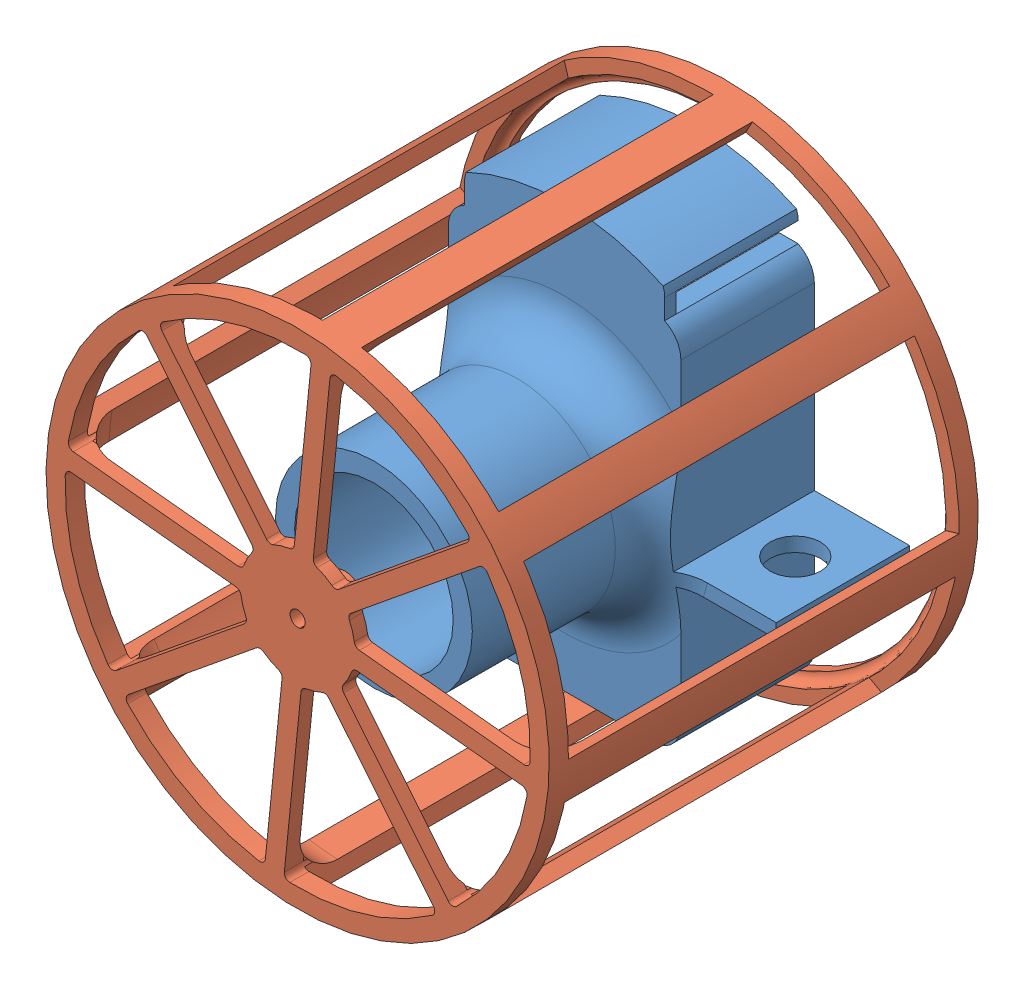
SolidWorks assembly Dumb Bot, configuration Default. Lengths in mm.
Overall size (90.82 90.82 57.15).
2 component instances, 2 part files, 2 mates.
Components (placement in the parent):
- Fly Wheel-1: Fly Wheel [Default] at (-42.9691 26.6526 21.4471) size (43.69 56.32 43.18)
- Case-1: Case [Default] at (-42.9691 26.6526 31.6071) x (0.473817 0.880623 0) z (0 0 1) size (67.06 67.06 57.15)
Mates (geometry in assembly coordinates):
- Concentric1: concentric aligned: cylinder of Fly Wheel-1 through (-42.9691 26.6526 21.4471) axis (0 0 1) radius 10.5705; cylinder of Case-1 through (-42.9691 26.6526 31.6071) axis (0 0 1) radius 1.016
- Distance1: distance = 3.81 mm anti-aligned: plane of Case-1 through (-43.8638 27.134 25.2571) normal (0 0 -1); plane of Fly Wheel-1 through (-42.9691 39.7631 21.4471) normal (0 0 1)
